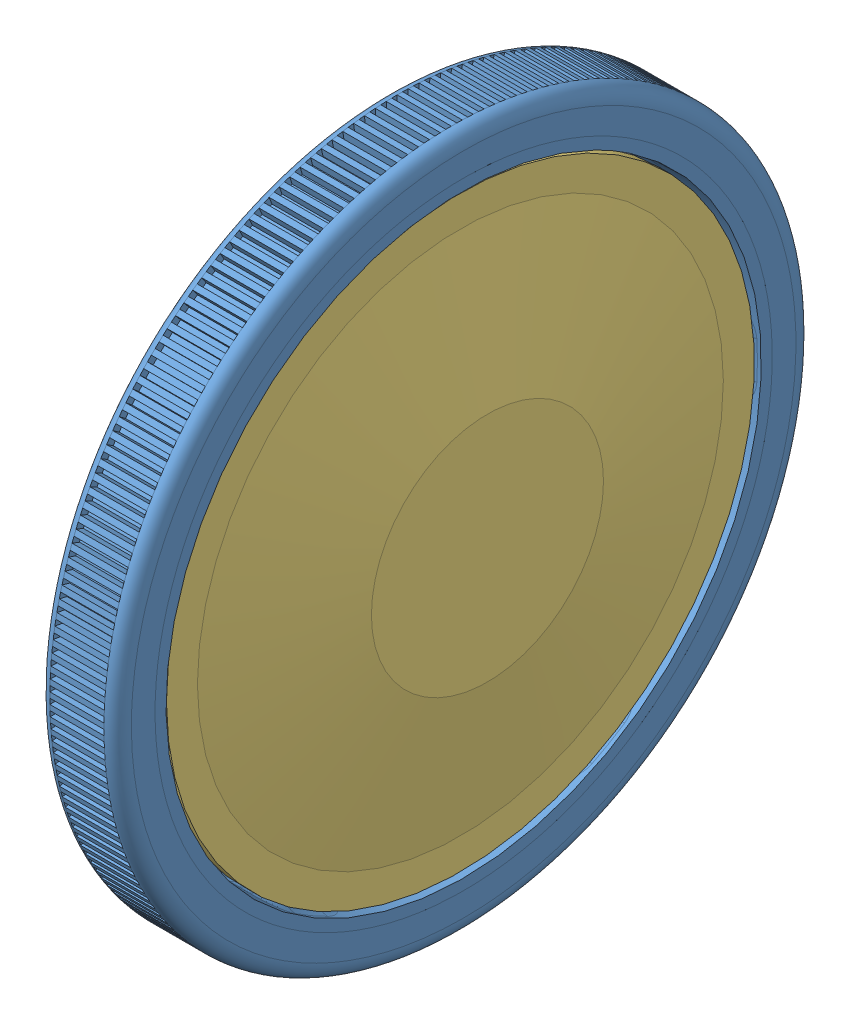
SolidWorks assembly HEL-03-01001-00, configuration Standard. Lengths in mm.
Overall size (19.78 90.76 90.48).
7 component instances, 4 part files, 8 mates.
Components (placement in the parent):
- HEL-06-01000-01-1: HEL-06-01000-01 [Standard] at origin size (11 90.76 90.48)
- HEL-06-01002-00-1: HEL-06-01002-00 [Standard] at (-5 0 -0.0001) x (0 1 0) z (-1 0 0) size (25.4 25.4 9.2)
- HEL-04-03000-01-1: HEL-04-03000-01 [Default] at (3.0756 0 0) size (10.5 76 76)
- socket head thin cap screw_din-8: socket head thin cap screw_din [DIN 7984 - M3 x 8 --- 6.5N] at (4.5 -8.2489 -4.7625) x (-1 0 0) z (0 0 -1) size (10 5.5 5.5)
- socket head thin cap screw_din-10: socket head thin cap screw_din [DIN 7984 - M3 x 8 --- 6.5N] at (4.5 8.2489 -4.7625) x (-1 0 0) z (0 0.866025 0.5) size (10 5.5 5.5)
- socket head thin cap screw_din-11: socket head thin cap screw_din [DIN 7984 - M3 x 8 --- 6.5N] at (4.5 8.2489 4.7625) x (-1 0 0) z (0 0 1) size (10 5.5 5.5)
- socket head thin cap screw_din-13: socket head thin cap screw_din [DIN 7984 - M3 x 8 --- 6.5N] at (4.5 -8.2489 4.7625) x (-1 0 0) z (0 -0.866025 -0.5) size (10 5.5 5.5)
Mates (geometry in assembly coordinates):
- Konzentrisch1: concentric anti-aligned: cone of HEL-06-01000-01-1 through (2.5 0 0) axis (1 0 0); cylinder of HEL-06-01002-00-1 through (-2.5 0 0) axis (-1 0 0) radius 3
- Konzentrisch2: concentric aligned: cone of HEL-06-01000-01-1 through (0 8.2489 -4.7625) axis (-1 0 0); cylinder of HEL-06-01002-00-1 through (-7.5 8.2489 -4.7625) axis (-1 0 0) radius 1.13
- Deckungsgleich12: coincident anti-aligned: plane of HEL-06-01000-01-1 through (2.5 0 0) normal (1 0 0); plane of socket head thin cap screw_din-8 through (2.5 -5.4989 -4.7625) normal (-1 0 0)
- Concentric5: concentric aligned: cylinder of socket head thin cap screw_din-8 through (36.25 -8.2489 -4.7625) axis (1 0 0) radius 1.5; cone of HEL-06-01000-01-1 through (0 -8.2489 -4.7625) axis (1 0 0)
- Coincident3: coincident aligned: plane of HEL-04-03000-01-1 through (3.0756 0 0) normal (0 0 1)
- Coincident4: coincident aligned: plane of HEL-04-03000-01-1 through (3.0756 0 0) normal (0 1 0)
- Coincident6: coincident anti-aligned: plane of HEL-06-01002-00-1 through (-2.5 0 0) normal (1 0 0); plane of HEL-06-01000-01-1 through (-2.5 0 0) normal (-1 0 0)
- Tangent9: tangent: circle of HEL-04-03000-01-1; torus of HEL-06-01000-01-1
